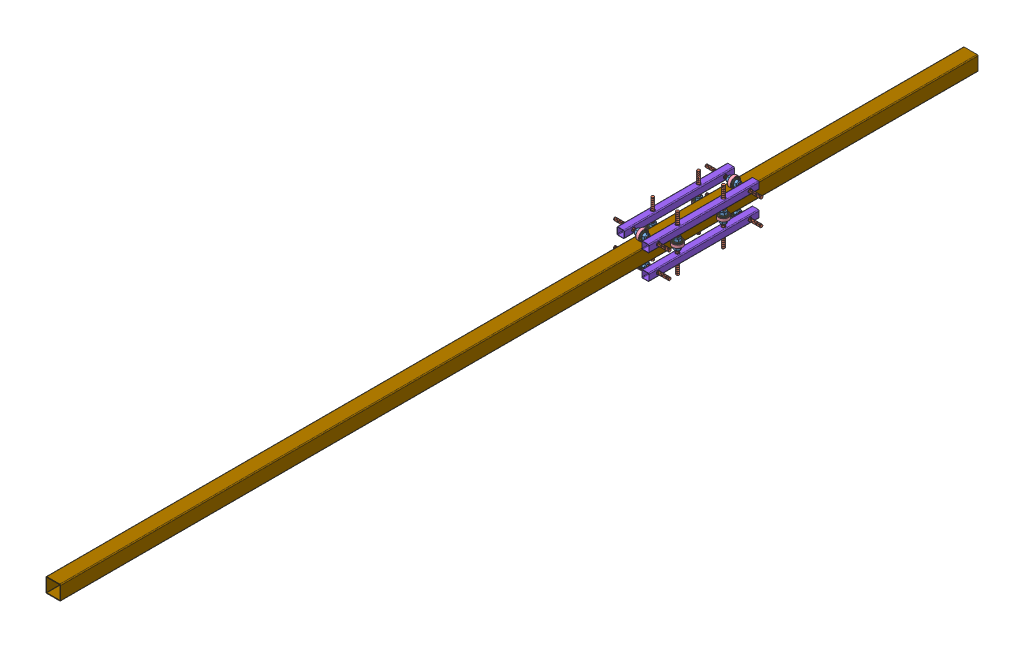
SolidWorks assembly CNC_SubAssembly2, configuration Default. Lengths in mm.
Overall size (121.11 121.11 2000).
157 component instances, 9 part files, 29 mates.
Components (placement in the parent):
- BB_Rod_Assembly-1: BB_Rod_Assembly [Default] at (27 -60 -333.8942) x (-0.532809 0 0.846236) z (-0.846236 0 -0.532809) size (23.24 121.11 23.24)
  - M8_self_lock_Nut-1: M8_self_lock_Nut [Valor predeterminado] at (0 71 0) x (-0.837169 0 -0.546944) z (0 -1 0) size (15.1 12 8.06)
  - M8_Threaded_Rod-1: M8_Threaded_Rod [Default] at origin size (6.18 121.11 6.93)
  - M8_Washer-1: M8_Washer [Default] at (0 63.5 0) x (1 0 0) z (0 1 0) size (15.5 15.5 1.5)
  - BB_Assembly-1: BB_Assembly [Default] at (0 60 0) x (0 -1 0) z (-0.058052 0 0.998314) size (7 22 22)
    - BB_OuterRing-1: BB_OuterRing [Default] at origin size (7 22 22)
    - BB_InnerRing-1: BB_InnerRing [Default] x (1 0 0) z (0 0.97954 -0.20125) size (7 13 13)
    - BB_Ball-1: BB_Ball [Default] at (0 1.61 7.8363) x (-1 0 0) z (0 -0.97954 0.20125) size (4.5 4.5 4.5)
    - BB_Cage-1: BB_Cage [Default] x (0 -0.20125 -0.97954) z (1 0 0) size (18 18 2.77)
    - BB_Ball-2: BB_Ball [Default] at (0 6.6796 4.4027) x (-1 0 0) z (0 -0.550334 0.834945) size (4.5 4.5 4.5)
    - BB_Ball-3: BB_Ball [Default] at (0 7.8363 -1.61) x (-1 0 0) z (0 0.20125 0.97954) size (4.5 4.5 4.5)
    - BB_Ball-4: BB_Ball [Default] at (0 4.4027 -6.6796) x (-1 0 0) z (0 0.834945 0.550334) size (4.5 4.5 4.5)
    - BB_Ball-5: BB_Ball [Default] at (0 -1.61 -7.8363) x (-1 0 0) z (0 0.97954 -0.20125) size (4.5 4.5 4.5)
    - BB_Ball-6: BB_Ball [Default] at (0 -6.6796 -4.4027) x (-1 0 0) z (0 0.550334 -0.834945) size (4.5 4.5 4.5)
    - BB_Ball-7: BB_Ball [Default] at (0 -7.8363 1.61) x (-1 0 0) z (0 -0.20125 -0.97954) size (4.5 4.5 4.5)
    - BB_Ball-8: BB_Ball [Default] at (0 -4.4027 6.6796) x (-1 0 0) z (0 -0.834945 -0.550334) size (4.5 4.5 4.5)
    - BB_Cage-2: BB_Cage [Default] x (0 0.20125 0.97954) z (-1 0 0) size (18 18 2.77)
  - M8_Washer-3: M8_Washer [Default] at (0 55 0) x (1 0 0) z (0 1 0) size (15.5 15.5 1.5)
  - M8_self_lock_Nut-15: M8_self_lock_Nut [Valor predeterminado] at (0 49 0) x (1 0 0) z (0 1 0) size (15.1 12 8.06)
- Square_Tubing_16mm-1: Square_Tubing_16mm [Default] at (27 27 -383.8942) size (16 16 240)
- BB_Rod_Assembly-2: BB_Rod_Assembly [Default] at (27 -60 -433.8942) x (0.999895 0 -0.014471) z (0.014471 0 0.999895) size (23.24 121.11 23.24)
  - M8_self_lock_Nut-1: M8_self_lock_Nut [Valor predeterminado] at (0 71 0) x (-0.837169 0 -0.546944) z (0 -1 0) size (15.1 12 8.06)
  - M8_Threaded_Rod-1: M8_Threaded_Rod [Default] at origin size (6.18 121.11 6.93)
  - M8_Washer-1: M8_Washer [Default] at (0 63.5 0) x (1 0 0) z (0 1 0) size (15.5 15.5 1.5)
  - BB_Assembly-1: BB_Assembly [Default] at (0 60 0) x (0 -1 0) z (-0.058052 0 0.998314) size (7 22 22)
    - BB_OuterRing-1: BB_OuterRing [Default] at origin size (7 22 22)
    - BB_InnerRing-1: BB_InnerRing [Default] x (1 0 0) z (0 0.97954 -0.20125) size (7 13 13)
    - BB_Ball-1: BB_Ball [Default] at (0 1.61 7.8363) x (-1 0 0) z (0 -0.97954 0.20125) size (4.5 4.5 4.5)
    - BB_Cage-1: BB_Cage [Default] x (0 -0.20125 -0.97954) z (1 0 0) size (18 18 2.77)
    - BB_Ball-2: BB_Ball [Default] at (0 6.6796 4.4027) x (-1 0 0) z (0 -0.550334 0.834945) size (4.5 4.5 4.5)
    - BB_Ball-3: BB_Ball [Default] at (0 7.8363 -1.61) x (-1 0 0) z (0 0.20125 0.97954) size (4.5 4.5 4.5)
    - BB_Ball-4: BB_Ball [Default] at (0 4.4027 -6.6796) x (-1 0 0) z (0 0.834945 0.550334) size (4.5 4.5 4.5)
    - BB_Ball-5: BB_Ball [Default] at (0 -1.61 -7.8363) x (-1 0 0) z (0 0.97954 -0.20125) size (4.5 4.5 4.5)
    - BB_Ball-6: BB_Ball [Default] at (0 -6.6796 -4.4027) x (-1 0 0) z (0 0.550334 -0.834945) size (4.5 4.5 4.5)
    - BB_Ball-7: BB_Ball [Default] at (0 -7.8363 1.61) x (-1 0 0) z (0 -0.20125 -0.97954) size (4.5 4.5 4.5)
    - BB_Ball-8: BB_Ball [Default] at (0 -4.4027 6.6796) x (-1 0 0) z (0 -0.834945 -0.550334) size (4.5 4.5 4.5)
    - BB_Cage-2: BB_Cage [Default] x (0 0.20125 0.97954) z (-1 0 0) size (18 18 2.77)
  - M8_Washer-3: M8_Washer [Default] at (0 55 0) x (1 0 0) z (0 1 0) size (15.5 15.5 1.5)
  - M8_self_lock_Nut-15: M8_self_lock_Nut [Valor predeterminado] at (0 49 0) x (1 0 0) z (0 1 0) size (15.1 12 8.06)
- Square_Tubing_16mm-2: Square_Tubing_16mm [Default] at (27 -27 -383.8942) size (16 16 240)
- BB_Rod_Assembly-3: BB_Rod_Assembly [Default] at (-60 27 -483.8942) x (0 -0.853939 -0.520374) z (0 -0.520374 0.853939) size (23.24 121.11 23.24)
  - M8_self_lock_Nut-1: M8_self_lock_Nut [Valor predeterminado] at (0 71 0) x (-0.837169 0 -0.546944) z (0 -1 0) size (15.1 12 8.06)
  - M8_Threaded_Rod-1: M8_Threaded_Rod [Default] at origin size (6.18 121.11 6.93)
  - M8_Washer-1: M8_Washer [Default] at (0 63.5 0) x (1 0 0) z (0 1 0) size (15.5 15.5 1.5)
  - BB_Assembly-1: BB_Assembly [Default] at (0 60 0) x (0 -1 0) z (-0.058052 0 0.998314) size (7 22 22)
    - BB_OuterRing-1: BB_OuterRing [Default] at origin size (7 22 22)
    - BB_InnerRing-1: BB_InnerRing [Default] x (1 0 0) z (0 0.97954 -0.20125) size (7 13 13)
    - BB_Ball-1: BB_Ball [Default] at (0 1.61 7.8363) x (-1 0 0) z (0 -0.97954 0.20125) size (4.5 4.5 4.5)
    - BB_Cage-1: BB_Cage [Default] x (0 -0.20125 -0.97954) z (1 0 0) size (18 18 2.77)
    - BB_Ball-2: BB_Ball [Default] at (0 6.6796 4.4027) x (-1 0 0) z (0 -0.550334 0.834945) size (4.5 4.5 4.5)
    - BB_Ball-3: BB_Ball [Default] at (0 7.8363 -1.61) x (-1 0 0) z (0 0.20125 0.97954) size (4.5 4.5 4.5)
    - BB_Ball-4: BB_Ball [Default] at (0 4.4027 -6.6796) x (-1 0 0) z (0 0.834945 0.550334) size (4.5 4.5 4.5)
    - BB_Ball-5: BB_Ball [Default] at (0 -1.61 -7.8363) x (-1 0 0) z (0 0.97954 -0.20125) size (4.5 4.5 4.5)
    - BB_Ball-6: BB_Ball [Default] at (0 -6.6796 -4.4027) x (-1 0 0) z (0 0.550334 -0.834945) size (4.5 4.5 4.5)
    - BB_Ball-7: BB_Ball [Default] at (0 -7.8363 1.61) x (-1 0 0) z (0 -0.20125 -0.97954) size (4.5 4.5 4.5)
    - BB_Ball-8: BB_Ball [Default] at (0 -4.4027 6.6796) x (-1 0 0) z (0 -0.834945 -0.550334) size (4.5 4.5 4.5)
    - BB_Cage-2: BB_Cage [Default] x (0 0.20125 0.97954) z (-1 0 0) size (18 18 2.77)
  - M8_Washer-3: M8_Washer [Default] at (0 55 0) x (1 0 0) z (0 1 0) size (15.5 15.5 1.5)
  - M8_self_lock_Nut-15: M8_self_lock_Nut [Valor predeterminado] at (0 49 0) x (1 0 0) z (0 1 0) size (15.1 12 8.06)
- BB_Rod_Assembly-4: BB_Rod_Assembly [Default] at (-60 27 -283.8942) x (0 -0.092758 0.995689) z (0 0.995689 0.092758) size (23.24 121.11 23.24)
  - M8_self_lock_Nut-1: M8_self_lock_Nut [Valor predeterminado] at (0 71 0) x (-0.837169 0 -0.546944) z (0 -1 0) size (15.1 12 8.06)
  - M8_Threaded_Rod-1: M8_Threaded_Rod [Default] at origin size (6.18 121.11 6.93)
  - M8_Washer-1: M8_Washer [Default] at (0 63.5 0) x (1 0 0) z (0 1 0) size (15.5 15.5 1.5)
  - BB_Assembly-1: BB_Assembly [Default] at (0 60 0) x (0 -1 0) z (-0.058052 0 0.998314) size (7 22 22)
    - BB_OuterRing-1: BB_OuterRing [Default] at origin size (7 22 22)
    - BB_InnerRing-1: BB_InnerRing [Default] x (1 0 0) z (0 0.97954 -0.20125) size (7 13 13)
    - BB_Ball-1: BB_Ball [Default] at (0 1.61 7.8363) x (-1 0 0) z (0 -0.97954 0.20125) size (4.5 4.5 4.5)
    - BB_Cage-1: BB_Cage [Default] x (0 -0.20125 -0.97954) z (1 0 0) size (18 18 2.77)
    - BB_Ball-2: BB_Ball [Default] at (0 6.6796 4.4027) x (-1 0 0) z (0 -0.550334 0.834945) size (4.5 4.5 4.5)
    - BB_Ball-3: BB_Ball [Default] at (0 7.8363 -1.61) x (-1 0 0) z (0 0.20125 0.97954) size (4.5 4.5 4.5)
    - BB_Ball-4: BB_Ball [Default] at (0 4.4027 -6.6796) x (-1 0 0) z (0 0.834945 0.550334) size (4.5 4.5 4.5)
    - BB_Ball-5: BB_Ball [Default] at (0 -1.61 -7.8363) x (-1 0 0) z (0 0.97954 -0.20125) size (4.5 4.5 4.5)
    - BB_Ball-6: BB_Ball [Default] at (0 -6.6796 -4.4027) x (-1 0 0) z (0 0.550334 -0.834945) size (4.5 4.5 4.5)
    - BB_Ball-7: BB_Ball [Default] at (0 -7.8363 1.61) x (-1 0 0) z (0 -0.20125 -0.97954) size (4.5 4.5 4.5)
    - BB_Ball-8: BB_Ball [Default] at (0 -4.4027 6.6796) x (-1 0 0) z (0 -0.834945 -0.550334) size (4.5 4.5 4.5)
    - BB_Cage-2: BB_Cage [Default] x (0 0.20125 0.97954) z (-1 0 0) size (18 18 2.77)
  - M8_Washer-3: M8_Washer [Default] at (0 55 0) x (1 0 0) z (0 1 0) size (15.5 15.5 1.5)
  - M8_self_lock_Nut-15: M8_self_lock_Nut [Valor predeterminado] at (0 49 0) x (1 0 0) z (0 1 0) size (15.1 12 8.06)
- Square_Tubing_16mm-3: Square_Tubing_16mm [Default] at (-27 -27 -383.8942) size (16 16 240)
- Square_Tubing_16mm-4: Square_Tubing_16mm [Default] at (-27 27 -383.8942) size (16 16 240)
- BB_Rod_Assembly-5: BB_Rod_Assembly [Default] at (-60 -27 -483.8942) x (0 -1 0) z (0 0 1) size (23.24 121.11 23.24)
  - M8_self_lock_Nut-1: M8_self_lock_Nut [Valor predeterminado] at (0 71 0) x (-0.837169 0 -0.546944) z (0 -1 0) size (15.1 12 8.06)
  - M8_Threaded_Rod-1: M8_Threaded_Rod [Default] at origin size (6.18 121.11 6.93)
  - M8_Washer-1: M8_Washer [Default] at (0 63.5 0) x (1 0 0) z (0 1 0) size (15.5 15.5 1.5)
  - BB_Assembly-1: BB_Assembly [Default] at (0 60 0) x (0 -1 0) z (-0.058052 0 0.998314) size (7 22 22)
    - BB_OuterRing-1: BB_OuterRing [Default] at origin size (7 22 22)
    - BB_InnerRing-1: BB_InnerRing [Default] x (1 0 0) z (0 0.97954 -0.20125) size (7 13 13)
    - BB_Ball-1: BB_Ball [Default] at (0 1.61 7.8363) x (-1 0 0) z (0 -0.97954 0.20125) size (4.5 4.5 4.5)
    - BB_Cage-1: BB_Cage [Default] x (0 -0.20125 -0.97954) z (1 0 0) size (18 18 2.77)
    - BB_Ball-2: BB_Ball [Default] at (0 6.6796 4.4027) x (-1 0 0) z (0 -0.550334 0.834945) size (4.5 4.5 4.5)
    - BB_Ball-3: BB_Ball [Default] at (0 7.8363 -1.61) x (-1 0 0) z (0 0.20125 0.97954) size (4.5 4.5 4.5)
    - BB_Ball-4: BB_Ball [Default] at (0 4.4027 -6.6796) x (-1 0 0) z (0 0.834945 0.550334) size (4.5 4.5 4.5)
    - BB_Ball-5: BB_Ball [Default] at (0 -1.61 -7.8363) x (-1 0 0) z (0 0.97954 -0.20125) size (4.5 4.5 4.5)
    - BB_Ball-6: BB_Ball [Default] at (0 -6.6796 -4.4027) x (-1 0 0) z (0 0.550334 -0.834945) size (4.5 4.5 4.5)
    - BB_Ball-7: BB_Ball [Default] at (0 -7.8363 1.61) x (-1 0 0) z (0 -0.20125 -0.97954) size (4.5 4.5 4.5)
    - BB_Ball-8: BB_Ball [Default] at (0 -4.4027 6.6796) x (-1 0 0) z (0 -0.834945 -0.550334) size (4.5 4.5 4.5)
    - BB_Cage-2: BB_Cage [Default] x (0 0.20125 0.97954) z (-1 0 0) size (18 18 2.77)
  - M8_Washer-3: M8_Washer [Default] at (0 55 0) x (1 0 0) z (0 1 0) size (15.5 15.5 1.5)
  - M8_self_lock_Nut-15: M8_self_lock_Nut [Valor predeterminado] at (0 49 0) x (1 0 0) z (0 1 0) size (15.1 12 8.06)
- BB_Rod_Assembly-6: BB_Rod_Assembly [Default] at (-27 -60 -333.8942) x (0.666967 0 -0.745087) z (0.745087 0 0.666967) size (23.24 121.11 23.24)
  - M8_self_lock_Nut-1: M8_self_lock_Nut [Valor predeterminado] at (0 71 0) x (-0.837169 0 -0.546944) z (0 -1 0) size (15.1 12 8.06)
  - M8_Threaded_Rod-1: M8_Threaded_Rod [Default] at origin size (6.18 121.11 6.93)
  - M8_Washer-1: M8_Washer [Default] at (0 63.5 0) x (1 0 0) z (0 1 0) size (15.5 15.5 1.5)
  - BB_Assembly-1: BB_Assembly [Default] at (0 60 0) x (0 -1 0) z (-0.058052 0 0.998314) size (7 22 22)
    - BB_OuterRing-1: BB_OuterRing [Default] at origin size (7 22 22)
    - BB_InnerRing-1: BB_InnerRing [Default] x (1 0 0) z (0 0.97954 -0.20125) size (7 13 13)
    - BB_Ball-1: BB_Ball [Default] at (0 1.61 7.8363) x (-1 0 0) z (0 -0.97954 0.20125) size (4.5 4.5 4.5)
    - BB_Cage-1: BB_Cage [Default] x (0 -0.20125 -0.97954) z (1 0 0) size (18 18 2.77)
    - BB_Ball-2: BB_Ball [Default] at (0 6.6796 4.4027) x (-1 0 0) z (0 -0.550334 0.834945) size (4.5 4.5 4.5)
    - BB_Ball-3: BB_Ball [Default] at (0 7.8363 -1.61) x (-1 0 0) z (0 0.20125 0.97954) size (4.5 4.5 4.5)
    - BB_Ball-4: BB_Ball [Default] at (0 4.4027 -6.6796) x (-1 0 0) z (0 0.834945 0.550334) size (4.5 4.5 4.5)
    - BB_Ball-5: BB_Ball [Default] at (0 -1.61 -7.8363) x (-1 0 0) z (0 0.97954 -0.20125) size (4.5 4.5 4.5)
    - BB_Ball-6: BB_Ball [Default] at (0 -6.6796 -4.4027) x (-1 0 0) z (0 0.550334 -0.834945) size (4.5 4.5 4.5)
    - BB_Ball-7: BB_Ball [Default] at (0 -7.8363 1.61) x (-1 0 0) z (0 -0.20125 -0.97954) size (4.5 4.5 4.5)
    - BB_Ball-8: BB_Ball [Default] at (0 -4.4027 6.6796) x (-1 0 0) z (0 -0.834945 -0.550334) size (4.5 4.5 4.5)
    - BB_Cage-2: BB_Cage [Default] x (0 0.20125 0.97954) z (-1 0 0) size (18 18 2.77)
  - M8_Washer-3: M8_Washer [Default] at (0 55 0) x (1 0 0) z (0 1 0) size (15.5 15.5 1.5)
  - M8_self_lock_Nut-15: M8_self_lock_Nut [Valor predeterminado] at (0 49 0) x (1 0 0) z (0 1 0) size (15.1 12 8.06)
- BB_Rod_Assembly-7: BB_Rod_Assembly [Default] at (-60 -27 -283.8942) x (0 -0.99604 -0.08891) z (0 -0.08891 0.99604) size (23.24 121.11 23.24)
  - M8_self_lock_Nut-1: M8_self_lock_Nut [Valor predeterminado] at (0 71 0) x (-0.837169 0 -0.546944) z (0 -1 0) size (15.1 12 8.06)
  - M8_Threaded_Rod-1: M8_Threaded_Rod [Default] at origin size (6.18 121.11 6.93)
  - M8_Washer-1: M8_Washer [Default] at (0 63.5 0) x (1 0 0) z (0 1 0) size (15.5 15.5 1.5)
  - BB_Assembly-1: BB_Assembly [Default] at (0 60 0) x (0 -1 0) z (-0.058052 0 0.998314) size (7 22 22)
    - BB_OuterRing-1: BB_OuterRing [Default] at origin size (7 22 22)
    - BB_InnerRing-1: BB_InnerRing [Default] x (1 0 0) z (0 0.97954 -0.20125) size (7 13 13)
    - BB_Ball-1: BB_Ball [Default] at (0 1.61 7.8363) x (-1 0 0) z (0 -0.97954 0.20125) size (4.5 4.5 4.5)
    - BB_Cage-1: BB_Cage [Default] x (0 -0.20125 -0.97954) z (1 0 0) size (18 18 2.77)
    - BB_Ball-2: BB_Ball [Default] at (0 6.6796 4.4027) x (-1 0 0) z (0 -0.550334 0.834945) size (4.5 4.5 4.5)
    - BB_Ball-3: BB_Ball [Default] at (0 7.8363 -1.61) x (-1 0 0) z (0 0.20125 0.97954) size (4.5 4.5 4.5)
    - BB_Ball-4: BB_Ball [Default] at (0 4.4027 -6.6796) x (-1 0 0) z (0 0.834945 0.550334) size (4.5 4.5 4.5)
    - BB_Ball-5: BB_Ball [Default] at (0 -1.61 -7.8363) x (-1 0 0) z (0 0.97954 -0.20125) size (4.5 4.5 4.5)
    - BB_Ball-6: BB_Ball [Default] at (0 -6.6796 -4.4027) x (-1 0 0) z (0 0.550334 -0.834945) size (4.5 4.5 4.5)
    - BB_Ball-7: BB_Ball [Default] at (0 -7.8363 1.61) x (-1 0 0) z (0 -0.20125 -0.97954) size (4.5 4.5 4.5)
    - BB_Ball-8: BB_Ball [Default] at (0 -4.4027 6.6796) x (-1 0 0) z (0 -0.834945 -0.550334) size (4.5 4.5 4.5)
    - BB_Cage-2: BB_Cage [Default] x (0 0.20125 0.97954) z (-1 0 0) size (18 18 2.77)
  - M8_Washer-3: M8_Washer [Default] at (0 55 0) x (1 0 0) z (0 1 0) size (15.5 15.5 1.5)
  - M8_self_lock_Nut-15: M8_self_lock_Nut [Valor predeterminado] at (0 49 0) x (1 0 0) z (0 1 0) size (15.1 12 8.06)
- BB_Rod_Assembly-8: BB_Rod_Assembly [Default] at (-27 -60 -433.8942) x (0.999918 0 -0.012811) z (0.012811 0 0.999918) size (23.24 121.11 23.24)
  - M8_self_lock_Nut-1: M8_self_lock_Nut [Valor predeterminado] at (0 71 0) x (-0.837169 0 -0.546944) z (0 -1 0) size (15.1 12 8.06)
  - M8_Threaded_Rod-1: M8_Threaded_Rod [Default] at origin size (6.18 121.11 6.93)
  - M8_Washer-1: M8_Washer [Default] at (0 63.5 0) x (1 0 0) z (0 1 0) size (15.5 15.5 1.5)
  - BB_Assembly-1: BB_Assembly [Default] at (0 60 0) x (0 -1 0) z (-0.058052 0 0.998314) size (7 22 22)
    - BB_OuterRing-1: BB_OuterRing [Default] at origin size (7 22 22)
    - BB_InnerRing-1: BB_InnerRing [Default] x (1 0 0) z (0 0.97954 -0.20125) size (7 13 13)
    - BB_Ball-1: BB_Ball [Default] at (0 1.61 7.8363) x (-1 0 0) z (0 -0.97954 0.20125) size (4.5 4.5 4.5)
    - BB_Cage-1: BB_Cage [Default] x (0 -0.20125 -0.97954) z (1 0 0) size (18 18 2.77)
    - BB_Ball-2: BB_Ball [Default] at (0 6.6796 4.4027) x (-1 0 0) z (0 -0.550334 0.834945) size (4.5 4.5 4.5)
    - BB_Ball-3: BB_Ball [Default] at (0 7.8363 -1.61) x (-1 0 0) z (0 0.20125 0.97954) size (4.5 4.5 4.5)
    - BB_Ball-4: BB_Ball [Default] at (0 4.4027 -6.6796) x (-1 0 0) z (0 0.834945 0.550334) size (4.5 4.5 4.5)
    - BB_Ball-5: BB_Ball [Default] at (0 -1.61 -7.8363) x (-1 0 0) z (0 0.97954 -0.20125) size (4.5 4.5 4.5)
    - BB_Ball-6: BB_Ball [Default] at (0 -6.6796 -4.4027) x (-1 0 0) z (0 0.550334 -0.834945) size (4.5 4.5 4.5)
    - BB_Ball-7: BB_Ball [Default] at (0 -7.8363 1.61) x (-1 0 0) z (0 -0.20125 -0.97954) size (4.5 4.5 4.5)
    - BB_Ball-8: BB_Ball [Default] at (0 -4.4027 6.6796) x (-1 0 0) z (0 -0.834945 -0.550334) size (4.5 4.5 4.5)
    - BB_Cage-2: BB_Cage [Default] x (0 0.20125 0.97954) z (-1 0 0) size (18 18 2.77)
  - M8_Washer-3: M8_Washer [Default] at (0 55 0) x (1 0 0) z (0 1 0) size (15.5 15.5 1.5)
  - M8_self_lock_Nut-15: M8_self_lock_Nut [Valor predeterminado] at (0 49 0) x (1 0 0) z (0 1 0) size (15.1 12 8.06)
- 32mm_Square_Tubing_2m-1: 32mm_Square_Tubing_2m [Default] at origin size (32 32 2000)
Mates (geometry in assembly coordinates):
- Concentric1: concentric anti-aligned: cylinder of BB_Rod_Assembly-1/M8_Threaded_Rod-1 through (27 60 -333.8942) axis (0 -1 0) radius 3; cylinder of Square_Tubing_16mm-1 through (27 19 -333.8942) axis (0 1 0) radius 4
- Concentric2: concentric anti-aligned: cylinder of Square_Tubing_16mm-1 through (27 19 -433.8942) axis (0 1 0) radius 4; cylinder of BB_Rod_Assembly-2/M8_Threaded_Rod-1 through (27 60 -433.8942) axis (0 -1 0) radius 3
- Concentric3: concentric anti-aligned: cylinder of BB_Rod_Assembly-1/M8_Threaded_Rod-1 through (27 60 -333.8942) axis (0 -1 0) radius 3; cylinder of Square_Tubing_16mm-2 through (27 -35 -333.8942) axis (0 1 0) radius 4
- Concentric4: concentric anti-aligned: cylinder of Square_Tubing_16mm-1 through (19 27 -283.8942) axis (1 0 0) radius 4; cylinder of BB_Rod_Assembly-4/M8_Threaded_Rod-1 through (60 27 -283.8942) axis (-1 0 0) radius 3
- Concentric5: concentric anti-aligned: cylinder of Square_Tubing_16mm-1 through (19 27 -483.8942) axis (1 0 0) radius 4; cylinder of BB_Rod_Assembly-3/M8_Threaded_Rod-1 through (60 27 -483.8942) axis (-1 0 0) radius 3
- Concentric6: concentric anti-aligned: cylinder of Square_Tubing_16mm-2 through (19 -27 -283.8942) axis (1 0 0) radius 4; cylinder of BB_Rod_Assembly-7/M8_Threaded_Rod-1 through (60 -27 -283.8942) axis (-1 0 0) radius 3
- Concentric7: concentric anti-aligned: cylinder of Square_Tubing_16mm-2 through (19 -27 -483.8942) axis (1 0 0) radius 4; cylinder of BB_Rod_Assembly-5/M8_Threaded_Rod-1 through (60 -27 -483.8942) axis (-1 0 0) radius 3
- Concentric8: concentric anti-aligned: cylinder of Square_Tubing_16mm-3 through (-35 -27 -283.8942) axis (1 0 0) radius 4; cylinder of BB_Rod_Assembly-7/M8_Threaded_Rod-1 through (60 -27 -283.8942) axis (-1 0 0) radius 3
- Concentric9: concentric anti-aligned: cylinder of BB_Rod_Assembly-4/M8_Threaded_Rod-1 through (60 27 -283.8942) axis (-1 0 0) radius 3; cylinder of Square_Tubing_16mm-4 through (-35 27 -283.8942) axis (1 0 0) radius 4
- Concentric10: concentric anti-aligned: cylinder of Square_Tubing_16mm-4 through (-27 19 -433.8942) axis (0 1 0) radius 4; cylinder of BB_Rod_Assembly-8/M8_Threaded_Rod-1 through (-27 60 -433.8942) axis (0 -1 0) radius 3
- Concentric11: concentric anti-aligned: cylinder of Square_Tubing_16mm-4 through (-27 19 -333.8942) axis (0 1 0) radius 4; cylinder of BB_Rod_Assembly-6/M8_Threaded_Rod-1 through (-27 60 -333.8942) axis (0 -1 0) radius 3
- Concentric12: concentric anti-aligned: cylinder of Square_Tubing_16mm-3 through (-27 -35 -333.8942) axis (0 1 0) radius 4; cylinder of BB_Rod_Assembly-6/M8_Threaded_Rod-1 through (-27 60 -333.8942) axis (0 -1 0) radius 3
- Coincident22: coordinate: point of 32mm_Square_Tubing_2m-1
- Tangent1: tangent anti-aligned: cylinder of BB_Rod_Assembly-1/BB_Assembly-1/BB_OuterRing-1 through (27 29.8426 -333.8942) axis (0 1 0) radius 11; plane of 32mm_Square_Tubing_2m-1 through (16 -14 -1000) normal (1 0 0)
- Tangent2: tangent anti-aligned: cylinder of BB_Rod_Assembly-2/BB_Assembly-1/BB_OuterRing-1 through (27 29.8426 -433.8942) axis (0 1 0) radius 11; plane of 32mm_Square_Tubing_2m-1 through (16 -14 -1000) normal (1 0 0)
- Tangent3: tangent anti-aligned: cylinder of BB_Rod_Assembly-4/BB_Assembly-1/BB_OuterRing-1 through (29.8426 27 -283.8942) axis (1 0 0) radius 11; plane of 32mm_Square_Tubing_2m-1 through (-14 16 -1000) normal (0 1 0)
- Tangent4: tangent anti-aligned: cylinder of BB_Rod_Assembly-3/BB_Assembly-1/BB_OuterRing-1 through (29.8426 27 -483.8942) axis (1 0 0) radius 11; plane of 32mm_Square_Tubing_2m-1 through (-14 16 -1000) normal (0 1 0)
- Tangent5: tangent anti-aligned: cylinder of BB_Rod_Assembly-6/BB_Assembly-1/BB_OuterRing-1 through (-27 29.8426 -333.8942) axis (0 1 0) radius 11; plane of 32mm_Square_Tubing_2m-1 through (-16 -14 -1000) normal (-1 0 0)
- Tangent6: tangent anti-aligned: cylinder of BB_Rod_Assembly-8/BB_Assembly-1/BB_OuterRing-1 through (-27 29.8426 -433.8942) axis (0 1 0) radius 11; plane of 32mm_Square_Tubing_2m-1 through (-16 -14 -1000) normal (-1 0 0)
- Tangent7: tangent anti-aligned: cylinder of BB_Rod_Assembly-7/BB_Assembly-1/BB_OuterRing-1 through (29.8426 -27 -283.8942) axis (1 0 0) radius 11; plane of 32mm_Square_Tubing_2m-1 through (-14 -16 -1000) normal (0 -1 0)
- Tangent8: tangent anti-aligned: cylinder of BB_Rod_Assembly-5/BB_Assembly-1/BB_OuterRing-1 through (29.8426 -27 -483.8942) axis (1 0 0) radius 11; plane of 32mm_Square_Tubing_2m-1 through (-14 -16 -1000) normal (0 -1 0)
- Width11: width anti-aligned: plane of 32mm_Square_Tubing_2m-1 through (-14 16 -1000) normal (0 1 0); plane of BB_Rod_Assembly-1/BB_Assembly-1/BB_OuterRing-1 through (-14 -16 -1000) normal (0 -1 0); plane of 32mm_Square_Tubing_2m-1 through (21.4802 -3.5 -326.1623) normal (0 -1 0); plane of BB_Rod_Assembly-1/BB_Assembly-1/BB_OuterRing-1 through (21.4802 3.5 -326.1623) normal (0 1 0)
- Width12: width anti-aligned: plane of BB_Rod_Assembly-2/BB_Assembly-1/BB_OuterRing-1 through (36.491 3.5 -433.48) normal (0 1 0); plane of 32mm_Square_Tubing_2m-1 through (36.491 -3.5 -433.48) normal (0 -1 0); plane of BB_Rod_Assembly-2/BB_Assembly-1/BB_OuterRing-1 through (-14 -16 -1000) normal (0 -1 0); plane of 32mm_Square_Tubing_2m-1 through (-14 16 -1000) normal (0 1 0)
- Width13: width anti-aligned: plane of 32mm_Square_Tubing_2m-1 through (16 -14 -1000) normal (1 0 0); plane of BB_Rod_Assembly-3/BB_Assembly-1/BB_OuterRing-1 through (-16 -14 -1000) normal (-1 0 0); plane of 32mm_Square_Tubing_2m-1 through (-3.5 18.6143 -488.3584) normal (-1 0 0); plane of BB_Rod_Assembly-3/BB_Assembly-1/BB_OuterRing-1 through (3.5 18.6143 -488.3584) normal (1 0 0)
- Width14: width anti-aligned: plane of 32mm_Square_Tubing_2m-1 through (16 -14 -1000) normal (1 0 0); plane of BB_Rod_Assembly-4/BB_Assembly-1/BB_OuterRing-1 through (-16 -14 -1000) normal (-1 0 0); plane of 32mm_Square_Tubing_2m-1 through (-3.5 26.6694 -274.3999) normal (-1 0 0); plane of BB_Rod_Assembly-4/BB_Assembly-1/BB_OuterRing-1 through (3.5 26.6694 -274.3999) normal (1 0 0)
- Width15: width anti-aligned: plane of 32mm_Square_Tubing_2m-1 through (-16 -14 -1000) normal (-1 0 0); plane of BB_Rod_Assembly-7/BB_Assembly-1/BB_OuterRing-1 through (16 -14 -1000) normal (1 0 0); plane of 32mm_Square_Tubing_2m-1 through (3.5 -36.4955 -284.1881) normal (1 0 0); plane of BB_Rod_Assembly-7/BB_Assembly-1/BB_OuterRing-1 through (-3.5 -36.4955 -284.1881) normal (-1 0 0)
- Width16: width anti-aligned: plane of 32mm_Square_Tubing_2m-1 through (-16 -14 -1000) normal (-1 0 0); plane of BB_Rod_Assembly-5/BB_Assembly-1/BB_OuterRing-1 through (16 -14 -1000) normal (1 0 0); plane of 32mm_Square_Tubing_2m-1 through (3.5 -36.484 -483.3427) normal (1 0 0); plane of BB_Rod_Assembly-5/BB_Assembly-1/BB_OuterRing-1 through (-3.5 -36.484 -483.3427) normal (-1 0 0)
- Width17: width aligned: plane of BB_Rod_Assembly-8/BB_Assembly-1/BB_OuterRing-1 through (-17.5097 3.5 -433.4642) normal (0 1 0); plane of 32mm_Square_Tubing_2m-1 through (-17.5097 -3.5 -433.4642) normal (0 -1 0); plane of BB_Rod_Assembly-8/BB_Assembly-1/BB_OuterRing-1 through (-14 16 -1000) normal (0 1 0); plane of 32mm_Square_Tubing_2m-1 through (-14 -16 -1000) normal (0 -1 0)
- Width18: width aligned: plane of BB_Rod_Assembly-6/BB_Assembly-1/BB_OuterRing-1 through (-20.2636 -3.5 -340.5927) normal (0 -1 0); plane of 32mm_Square_Tubing_2m-1 through (-20.2636 3.5 -340.5927) normal (0 1 0); plane of BB_Rod_Assembly-6/BB_Assembly-1/BB_OuterRing-1 through (-14 -16 -1000) normal (0 -1 0); plane of 32mm_Square_Tubing_2m-1 through (-14 16 -1000) normal (0 1 0)
